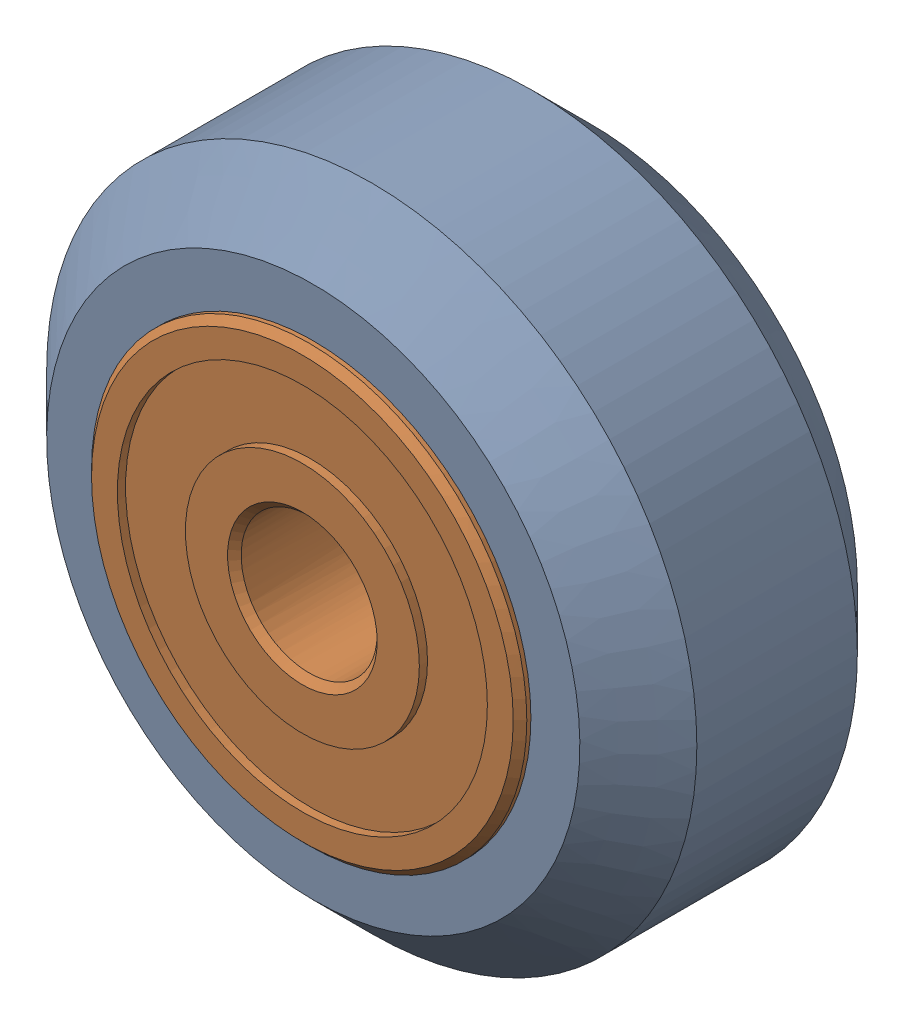
SolidWorks assembly Xtreme Solid V Wheel Assembly_3, configuration Default. Lengths in mm.
Overall size (23.9 23.9 11).
3 component instances, 2 part files, 0 mates.
Components (placement in the parent):
- Xtreme Solid V Wheel-1: Xtreme Solid V Wheel [Default] at (-154.85 -25 30) x (0 0 1) z (-1 0 0) size (10.2 23.9 23.9)
- Wheel+Kit+-+5x16x5mm+Sealed+Radial+Ball+Bearing.step.f3d-1: Wheel+Kit+-+5x16x5mm+Sealed+Radial+Ball+Bearing.step.f3d [Default] at (-154.85 -25 30) x (0 1 0) z (-1 0 0) size (16 5 16)
- Wheel+Kit+-+5x16x5mm+Sealed+Radial+Ball+Bearing.step.f3d-2: Wheel+Kit+-+5x16x5mm+Sealed+Radial+Ball+Bearing.step.f3d [Default] at (-154.85 -25 30) x (0 1 0) z (1 0 0) size (16 5 16)
